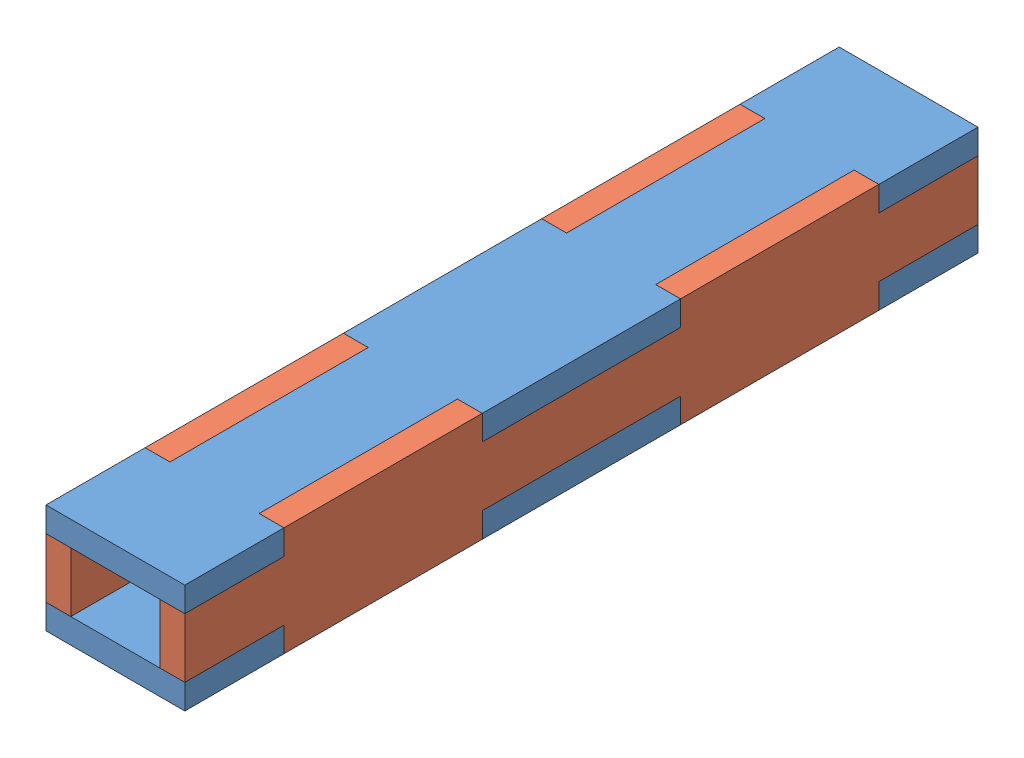
SolidWorks assembly ChimneyAcrylic, configuration Default. Lengths in mm.
Overall size (17.78 13.97 101.6).
4 component instances, 2 part files, 9 mates.
Components (placement in the parent):
- ChimneyShort-1: ChimneyShort [Default] at (31.268 48.0145 129.9306) size (17.78 3.17 101.6)
- ChimneyLong-1: ChimneyLong [Default] at (49.048 40.3945 129.9306) x (0 1 0) z (0 0 1) size (13.97 3.17 101.6)
- ChimneyShort-2: ChimneyShort [Default] at (31.268 37.2195 129.9306) size (17.78 3.17 101.6)
- ChimneyLong-2: ChimneyLong [Default] at (31.268 48.0145 129.9306) x (0 -1 0) z (0 0 1) size (13.97 3.17 101.6)
Mates (geometry in assembly coordinates):
- Coincident1: coincident anti-aligned: line of ChimneyLong-1 through (45.873 37.2195 41.0306) axis (0 0 1); line of ChimneyShort-2 through (45.873 37.2195 66.4306) axis (0 0 -1)
- Coincident2: coincident anti-aligned: plane of ChimneyLong-1 through (45.873 40.3945 129.9306) normal (-1 0 0); plane of ChimneyShort-2 through (45.873 40.3945 41.0306) normal (1 0 0)
- Coincident3: coincident: line of ChimneyLong-1 through (45.873 40.3945 28.3306) axis (0 1 0); plane of ChimneyShort-2 through (31.268 40.3945 28.3306) normal (0 0 -1)
- Coincident4: coincident aligned: plane of ChimneyShort-1 through (31.268 51.1895 28.3306) normal (0 0 -1); plane of ChimneyShort-2 through (31.268 40.3945 28.3306) normal (0 0 -1)
- Coincident5: coincident anti-aligned: plane of ChimneyShort-1 through (31.268 48.0145 129.9306) normal (0 -1 0); plane of ChimneyLong-1 through (45.873 48.0145 129.9306) normal (0 1 0)
- Coincident6: coincident: line of ChimneyShort-1 through (49.048 51.1895 41.0306) axis (0 0 -1); plane of ChimneyLong-1 through (49.048 40.3945 129.9306) normal (1 0 0)
- Coincident7: coincident aligned: plane of ChimneyShort-2 through (31.268 40.3945 28.3306) normal (0 0 -1); plane of ChimneyLong-2 through (34.443 48.0145 28.3306) normal (0 0 -1)
- Coincident8: coincident anti-aligned: plane of ChimneyShort-2 through (31.268 40.3945 129.9306) normal (0 1 0); plane of ChimneyLong-2 through (34.443 40.3945 129.9306) normal (0 -1 0)
- Coincident9: coincident aligned: plane of ChimneyShort-2 through (31.268 40.3945 41.0306) normal (-1 0 0); plane of ChimneyLong-2 through (31.268 48.0145 129.9306) normal (-1 0 0)
